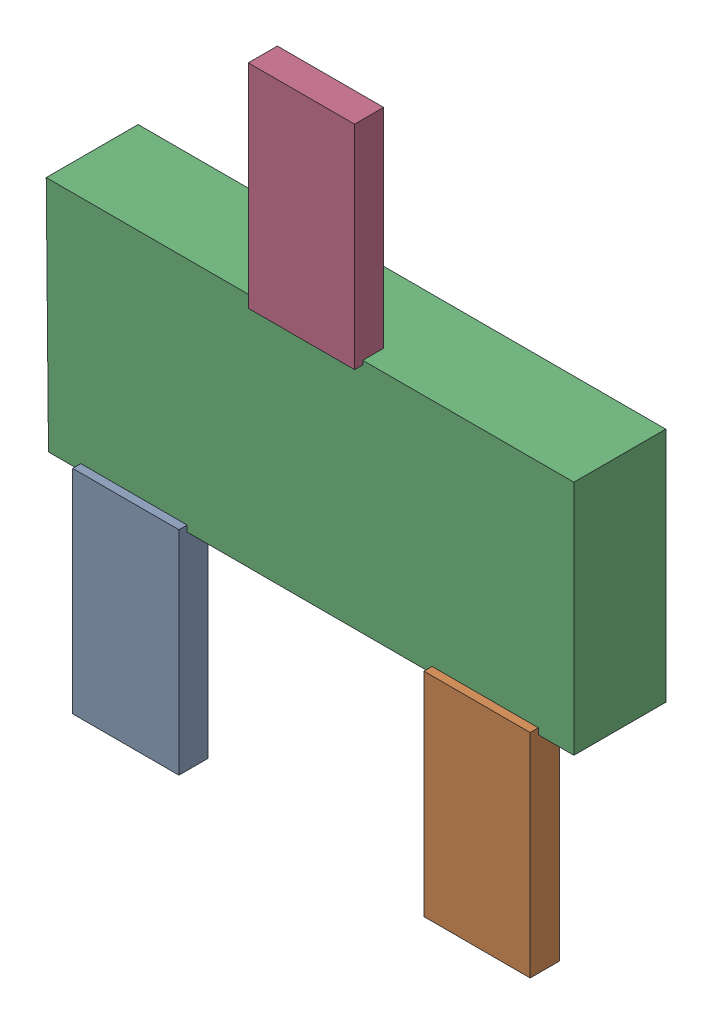
SolidWorks assembly Q1, configuration Default. Lengths in mm.
Overall size (2.9 3.58 0.55).
8 component instances, 2 part files, 0 mates.
Components (placement in the parent):
- 432143248-1: 432143248 [Default] at (33.3823 18.7992 -0.5715) size (0.58 1.17 0.16)
  - Extruded (36)-1: Extruded (36) [Default] at origin size (0.58 1.17 0.16)
- 432143248_1-1: 432143248_1 [Default] at (35.3127 18.7992 -0.5715) size (0.58 1.17 0.16)
  - Extruded (36)-1: Extruded (36) [Default] at origin size (0.58 1.17 0.16)
- 692618624-1: 692618624 [Default] at (34.35 20 -0.9615) size (2.9 1.3 0.5)
  - Extruded (37)-1: Extruded (37) [Default] at origin size (2.9 1.3 0.5)
- 432143248_2-1: 432143248_2 [Default] at (34.3475 21.2122 -0.5715) size (0.58 1.17 0.16)
  - Extruded (36)-1: Extruded (36) [Default] at origin size (0.58 1.17 0.16)
